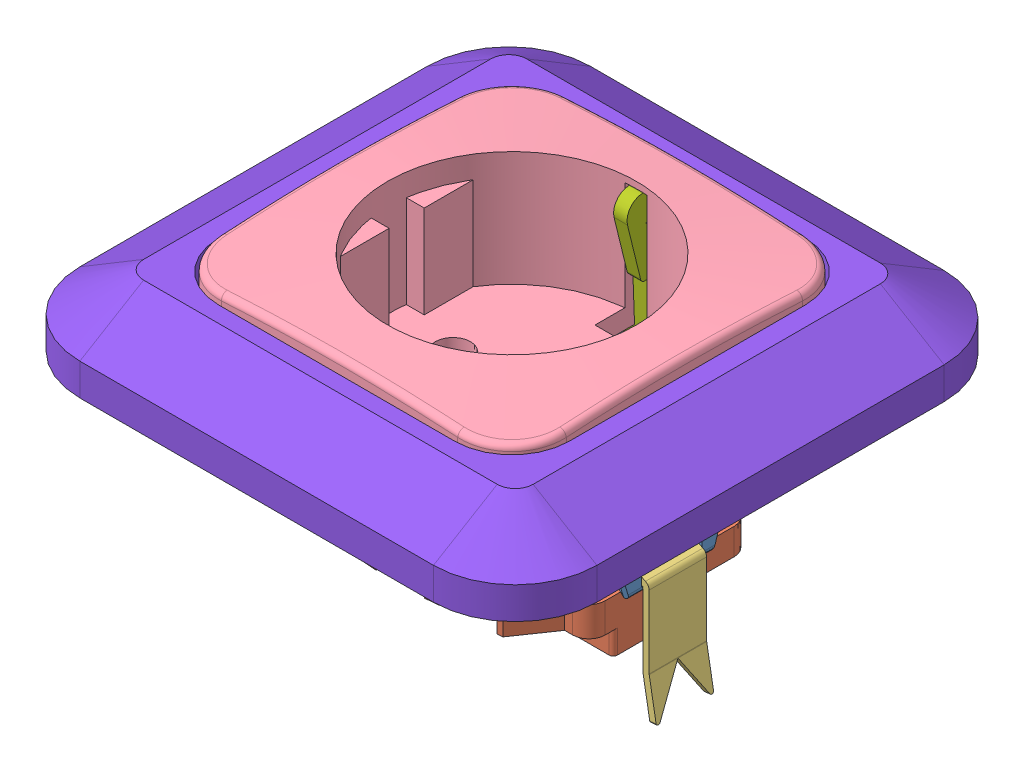
SolidWorks assembly Steckdose_1er, configuration Standard. Lengths in mm.
Overall size (81 49.07 80).
10 component instances, 8 part files, 3 mates.
Components (placement in the parent):
- Steckdose-1: Steckdose [Standard] at (48.5208 13.0547 -6.2011) size (71 49.07 71)
  - Montageplatte.02-1: Montageplatte.02 [Standard] at (-76.9981 11 50.9191) x (1 0 0) z (0 1 0) size (71 71 18.97)
  - Halter-1: Halter [Standard] at (-76.9981 11 50.9191) x (1 0 0) z (0 1 0) size (45.97 31.9 15.37)
  - Kralle.04-1: Kralle.04 [Standard] at (-74.3121 12.4168 50.9191) x (0.996195 -0.087156 0) z (0.087156 0.996195 0) size (8.78 9 23.36)
  - Kralle.04-2: Kralle.04 [Standard] at (74.3121 12.4168 -50.9191) x (-0.996195 -0.087156 0) z (-0.087156 0.996195 0) size (8.78 9 23.36)
  - Buchse-1: Buchse [Standard] at (-76.9981 11 50.9191) x (1 0 0) z (0 1 0) size (64.03 64.03 27)
  - Stromklemme_1.02-1: Stromklemme_1.02 [Standard] at (-76.9981 11 50.7921) x (1 0 0) z (0 1 0) size (8.38 19.82 12.51)
  - Stromklemme_2.02-1: Stromklemme_2.02 [Standard] at (-76.9981 11 50.7921) x (1 0 0) z (0 1 0) size (8.38 19.82 12.51)
  - Erdleiter-1: Erdleiter [Standard] at (-76.9981 11 50.9191) x (1 0 0) z (0 1 0) size (7.24 44.01 27.12)
- Wandplatte-1: Wandplatte [1er] at (8.0208 24.0547 33.7989) x (1 0 0) z (0 1 0) size (81 80 11)
Mates (geometry in assembly coordinates):
- Abstand1: distance = 0.5 mm anti-aligned: plane of Wandplatte-1 through (30.0208 18.0547 21.2989) normal (0 0 -1); plane of Steckdose-1/Buchse-1 through (67.0208 18.0547 20.7989) normal (0 0 1)
- Deckungsgleich2: coincident anti-aligned: plane of Steckdose-1/Buchse-1 through (48.5208 18.0547 20.2989) normal (0 -1 0); plane of Wandplatte-1 through (30.0208 18.0547 12.2989) normal (0 1 0)
- Abstand2: distance = 0.5 mm anti-aligned: plane of Steckdose-1/Buchse-1 through (21.5208 18.0547 12.2989) normal (-1 0 0); plane of Wandplatte-1 through (21.0208 18.0547 -24.7011) normal (1 0 0)
